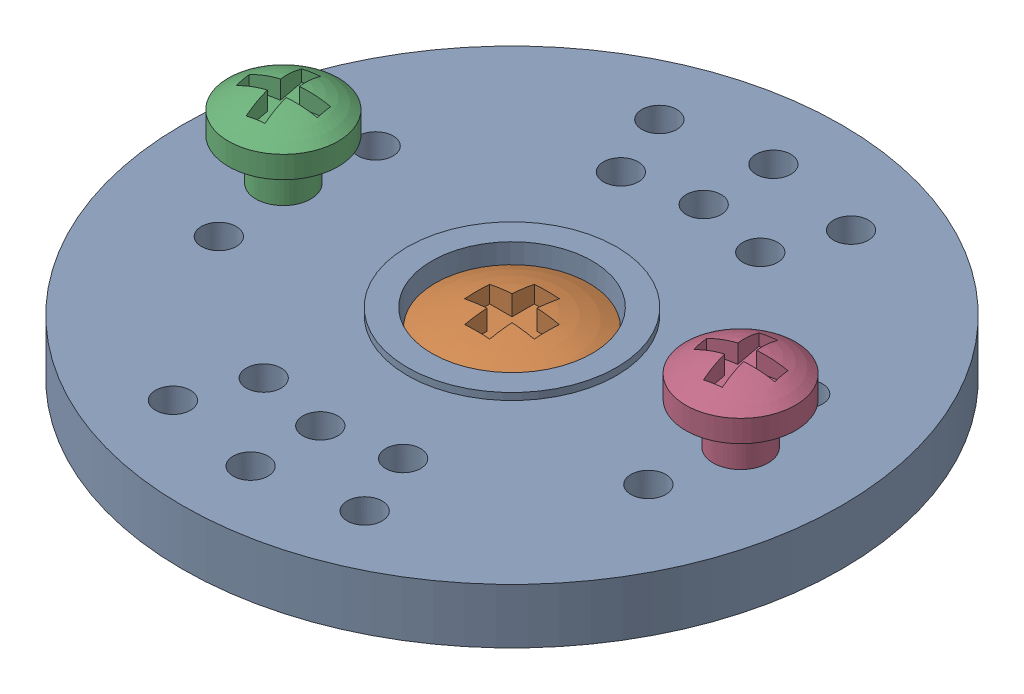
SolidWorks assembly SERVO-DIAL-ASSEMBLY, configuration Default. Lengths in mm.
Overall size (24.03 9.09 24.03).
4 component instances, 3 part files, 6 mates.
Components (placement in the parent):
- Servo-Dial-1: Servo-Dial [Default] at origin size (24.03 4.45 24.03)
- Servo-Screw-1: Servo-Screw [Default] at (0 4.445 0) size (5.59 6.32 5.59)
- Screw-01-3: Screw-01 [Default] at (-8.3312 -0.285 0) x (0.185376 0 0.982668) z (0 -1 0) size (4 4 7.47)
- Screw-01-4: Screw-01 [Default] at (8.3312 -0.285 0) x (0.185376 0 0.982668) z (0 -1 0) size (4 4 7.47)
Mates (geometry in assembly coordinates):
- Concentric2: concentric anti-aligned: cylinder of Servo-Dial-1 through (0 4.445 0) axis (0 -1 0) radius 1.5875; cylinder of Servo-Screw-1 through (0 4.445 0) axis (0 1 0) radius 0.9466
- Coincident1: coincident anti-aligned: plane of Servo-Dial-1 through (0 3.175 0) normal (0 1 0); plane of Servo-Screw-1 through (0.9466 3.175 0) normal (0 -1 0)
- Concentric3: concentric anti-aligned: cylinder of Servo-Dial-1 through (-8.3312 0 0) axis (0 1 0) radius 0.635; cylinder of Screw-01-3 through (-8.3312 -0.285 0) axis (0 -1 0) radius 1
- Distance1: distance = 1.524 mm anti-aligned: plane of Servo-Dial-1 through (3.81 4.191 0) normal (0 1 0); plane of Screw-01-3 through (-8.1458 5.715 0.9827) normal (0 -1 0)
- Concentric4: concentric anti-aligned: cylinder of Servo-Dial-1 through (8.3312 0 0) axis (0 1 0) radius 0.635; cylinder of Screw-01-4 through (8.3312 -0.285 0) axis (0 -1 0) radius 1
- Distance2: distance = 1.524 mm anti-aligned: plane of Servo-Dial-1 through (3.81 4.191 0) normal (0 1 0); plane of Screw-01-4 through (8.5166 5.715 0.9827) normal (0 -1 0)
